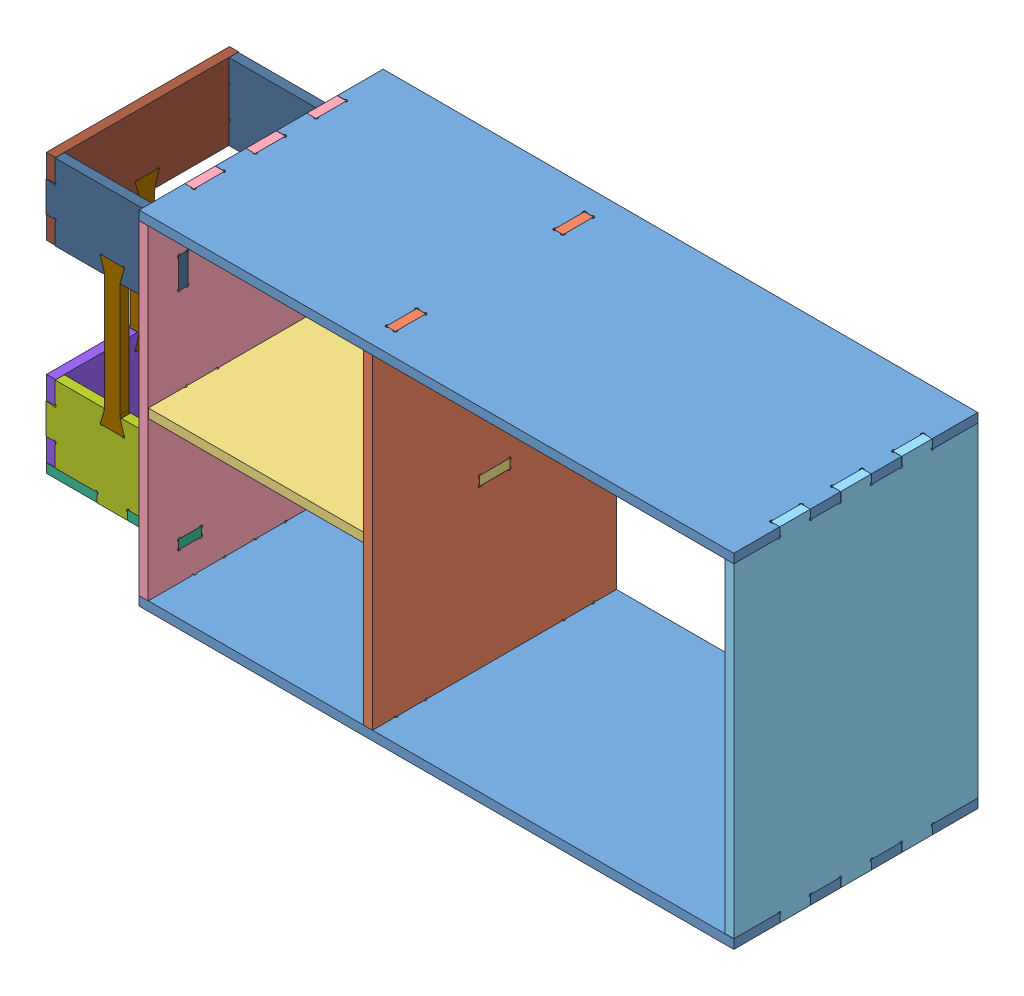
SolidWorks assembly Mueble, configuration Predeterminado. Lengths in mm.
Overall size (942.05 450 320.46).
17 component instances, 11 part files, 19 mates.
Components (placement in the parent):
- Superior_Base-1: Superior_Base [Predeterminado] at (-455.7983 80.8743 940) size (780 12 320)
- Superior_Base-2: Superior_Base [Predeterminado] at (-455.7983 -357.1257 940) size (780 12 320)
- Div_Vertical-1: Div_Vertical [Predeterminado] at (-149.6983 -345.1257 620) x (0 0 1) z (0 -1 0) size (320 12.1 450)
- DivisionHorizontal-1: DivisionHorizontal [Predeterminado] at (-443.6983 -138.0257 940) size (306 12 320)
- TapaLateral_izq-1: TapaLateral_izq [Predeterminado] at (-443.7983 -345.1257 620.2) x (0 0 1) z (0 -1 0) size (320 12 450)
- TapaLateral_der-1: TapaLateral_der [Predeterminado] at (312.2017 -345.1257 939.7387) x (0 0 -1) z (0 -1 0) size (320 12 450)
- Porta_Paraguas-1: Porta_Paraguas [Predeterminado] at (-295.4817 -281.6793 783.2754) x (0 0 1) z (-1 0 0) size (240.64 364.5 174.05)
  - P_base-1: P_base [Predeterminado] at (-123.7142 -25.5418 322.3166) size (240.64 12 174)
  - P_base_lateral-1: P_base_lateral [Predeterminado] at (-123.0754 86.4582 310.3666) x (0 0 1) z (1 0 0) size (162 112 12)
  - P_base_tapa-1: P_base_tapa [Predeterminado] at (-123.7142 86.6263 322.3166) x (1 0 0) z (0 1 0) size (240 12 112.17)
  - P_largueros-1: P_largueros [Predeterminado] at (104.9246 239.0936 235.3666) x (0 0 -1) z (1 0 0) size (31.31 192.94 12)
  - P_base_lateral-2: P_base_lateral [Predeterminado] at (104.9246 86.4582 310.3666) x (0 0 1) z (1 0 0) size (162 112 12)
  - P_largueros-2: P_largueros [Predeterminado] at (-3.6254 239.2617 310.3166) size (31.31 192.94 12)
  - P_largueros-3: P_largueros [Predeterminado] at (-111.0754 86.1582 235.3166) x (0 0 -1) z (-1 0 0) size (31.31 192.94 12)
  - P_lateral-1: P_lateral [Predeterminado] at (104.9246 238.7936 160.3166) x (0 0 -1) z (1 0 0) size (174 100 12)
  - P_tapa-1: P_tapa [Predeterminado] at (-123.7142 238.9617 310.3166) x (1 0 0) z (0 -1 0) size (240 12 100)
  - P_lateral-2: P_lateral [Predeterminado] at (-123.0754 238.7936 160.3166) x (0 0 -1) z (1 0 0) size (174 100 12)
Mates (geometry in assembly coordinates):
- Coincidente1: coincident aligned: plane of Superior_Base-1 through (-455.7983 92.8743 880.0387) normal (-1 0 0); plane of Superior_Base-2 through (-455.7983 -345.1257 880.0387) normal (-1 0 0)
- Coincidente4: coincident anti-aligned: plane of Superior_Base-1 through (-443.7983 92.8743 876.9194) normal (-1 0 0); plane of TapaLateral_izq-1 through (-443.7983 -346.0325 679.2932) normal (1 0 0)
- Coincidente6: coincident aligned: plane of Superior_Base-1 through (313.1085 92.8743 878.8319) normal (0 1 0); plane of TapaLateral_izq-1 through (-455.7983 92.8743 880.2) normal (0 1 0)
- Coincidente11: coincident aligned: plane of Superior_Base-2 through (313.1085 -357.1257 879.0932) normal (0 -1 0); plane of ? through (312.2017 -357.1257 720) normal (0 -1 0)
- Coincidente12: coincident anti-aligned: plane of Superior_Base-2 through (324.2017 -345.1257 680) normal (0 0 1); plane of ? through (312.2017 -357.1257 680) normal (0 0 -1)
- Coincidente13: coincident anti-aligned: plane of Superior_Base-2 through (312.2017 -345.1257 843) normal (1 0 0); plane of ? through (312.2017 -345.1257 620) normal (-1 0 0)
- Coincidente17: coincident aligned: plane of Superior_Base-1 through (313.1085 92.8743 878.8319) normal (0 1 0); plane of Div_Vertical-1 through (-161.7983 92.8743 870) normal (0 1 0)
- Coincidente18: coincident anti-aligned: plane of Superior_Base-1 through (-161.7983 92.8743 907) normal (1 0 0); plane of Div_Vertical-1 through (-161.7983 81.7812 649.0932) normal (-1 0 0)
- Coincidente24: coincident anti-aligned: plane of Superior_Base-1 through (312.2017 92.8743 682.9) normal (1 0 0); plane of TapaLateral_der-1 through (312.2017 -346.0325 880.6456) normal (-1 0 0)
- Coincidente25: coincident anti-aligned: plane of Superior_Base-1 through (315.2017 92.8743 879.7387) normal (0 0 -1); plane of TapaLateral_der-1 through (324.2017 92.8743 879.7387) normal (0 0 1)
- Coincidente26: coincident aligned: plane of Superior_Base-1 through (313.1085 92.8743 878.8319) normal (0 1 0); plane of TapaLateral_der-1 through (324.2017 92.8743 759.7387) normal (0 1 0)
- Coincidente27: coincident anti-aligned: plane of Superior_Base-1 through (-158.7983 92.8743 910) normal (0 0 -1); plane of Div_Vertical-1 through (-161.7983 83.8743 910) normal (0 0 1)
- Coincidente28: coincident aligned: plane of Div_Vertical-1 through (-149.6983 81.7812 649.0932) normal (1 0 0); plane of DivisionHorizontal-1 through (-149.6983 -126.0257 800) normal (1 0 0)
- Coincidente29: coincident anti-aligned: plane of Div_Vertical-1 through (-161.7983 -126.0257 762.997) normal (0 -1 0); plane of DivisionHorizontal-1 through (-160.7915 -126.0257 800.9068) normal (0 1 0)
- Coincidente30: coincident aligned: plane of Div_Vertical-1 through (-161.7983 80.8743 940) normal (0 0 1); plane of DivisionHorizontal-1 through (-443.6983 -126.0257 940) normal (0 0 1)
- Coincidente32: coincident aligned: plane of TapaLateral_izq-1 through (-443.7983 -346.0325 679.2932) normal (1 0 0); plane of Porta_Paraguas-1/P_lateral-2 through (-443.7983 27.1143 672.2) normal (1 0 0)
- Coincidente33: coincident anti-aligned: plane of TapaLateral_izq-1 through (-455.7983 27.1143 669.2) normal (0 -1 0); plane of Porta_Paraguas-1/P_lateral-2 through (-443.7983 27.1143 672.2) normal (0 1 0)
- Coincidente34: coincident anti-aligned: plane of TapaLateral_izq-1 through (-455.7983 -9.9857 672.2) normal (0 0 -1); plane of Porta_Paraguas-1/P_lateral-2 through (-454.855 -13.829 672.2) normal (0 0 1)
- Coincidente35: coincident anti-aligned: plane of DivisionHorizontal-1 through (-455.6983 -126.0257 670) normal (0 0 -1); plane of TapaLateral_izq-1 through (-455.7983 -129.0257 670) normal (0 0 1)
